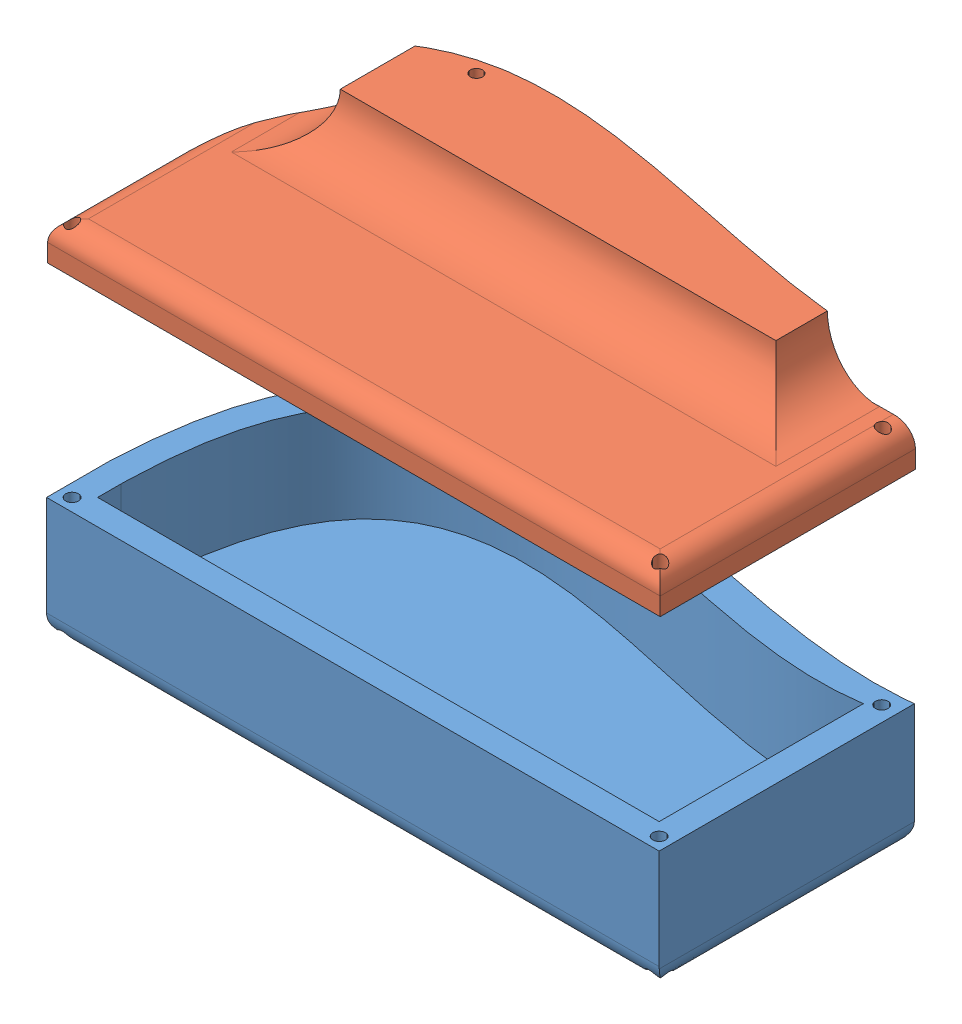
SolidWorks assembly device assembly, configuration Default. Lengths in mm.
Overall size (131.61 83.81 65.64).
2 component instances, 2 part files, 2 mates.
Components (placement in the parent):
- device housing-1: device housing [Default] at (-31.1702 5.2662 53.8947) size (131.61 27.7 65.64)
- Lid of device-1: Lid of device [Default] at (-31.2859 64.471 53.7284) size (114.3 18.24 58.31)
Mates (geometry in assembly coordinates):
- Concentric1: concentric anti-aligned: cylinder of Top of device-1 through (-48.0571 2.5588 60.1337) axis (0 1 0) radius 1.1906; cylinder of Lid of device-1 through (-48.0571 70.4364 60.1337) axis (0 -1 0) radius 1.143
- Parallel2: parallel aligned: plane of Top of device-1 through (-50.4384 25.4188 62.515) normal (0 0 1); plane of Lid of device-1 through (-50.3431 70.4364 62.4197) normal (0 0 1)
